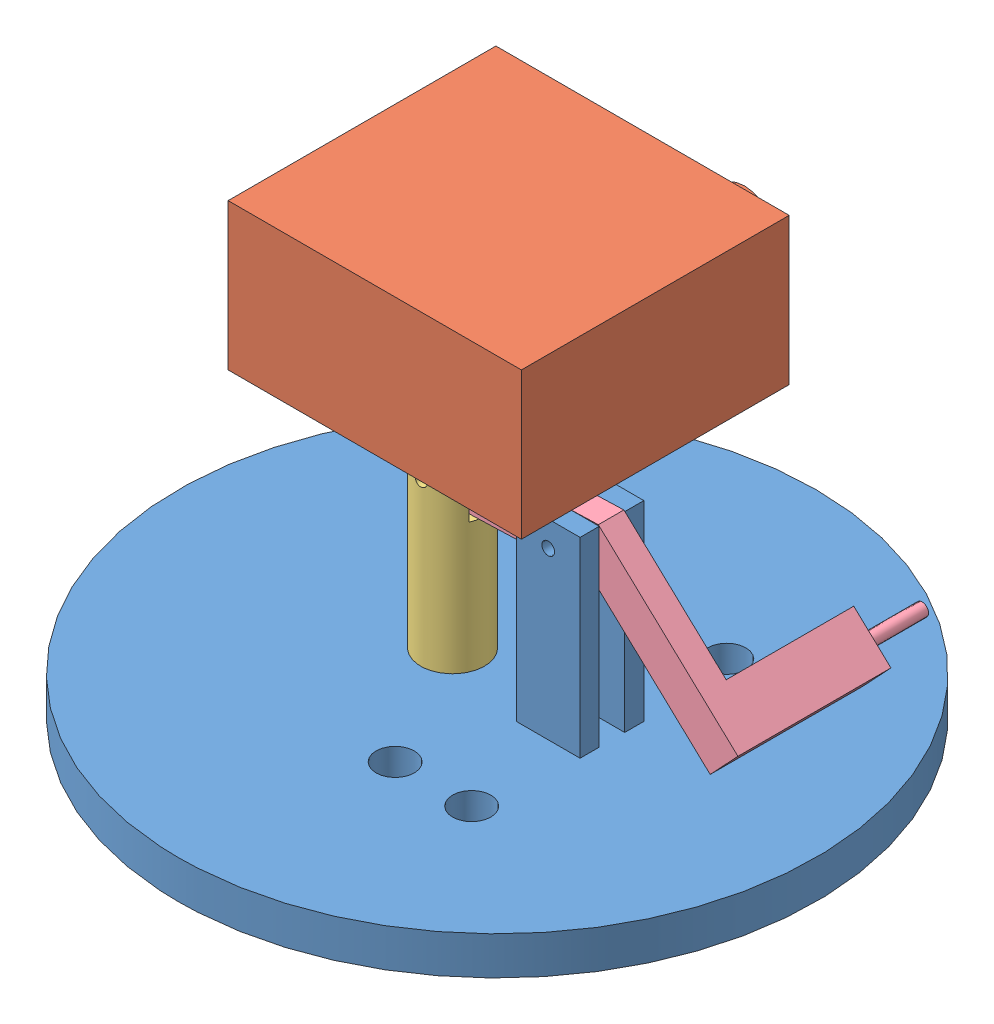
SolidWorks assembly Rückseite, configuration Standard. Lengths in mm.
Overall size (50 36.32 50).
4 component instances, 4 part files, 6 mates.
Components (placement in the parent):
- Backside-1: Backside [Standard] at (-0.7502 -6.4244 50) size (50 18 50)
- servo-1: servo [Standard] at (-8.4227 28.0756 59.9289) x (1 0 0) z (0 1 0) size (23 24.5 11.5)
- Drücker-1: Drücker [Standard] at (-2.5879 -8.2484 21.7522) size (5 20 5)
- Hebel-1: Hebel [Standard] at (9.2498 9.5756 49) x (0.999476 0.032383 0) z (0 0 1) size (25.61 12.86 17)
Mates (geometry in assembly coordinates):
- Konzentrisch1: concentric aligned: cylinder of Drücker-1 through (-0.7502 11.7516 50) axis (0 -1 0) radius 2.5; cylinder of Backside-1 through (-0.7502 -3.4244 50) axis (0 -1 0) radius 2.5
- Konzentrisch2: concentric anti-aligned: cylinder of Backside-1 through (9.2498 9.5756 42.5) axis (0 0 1) radius 0.5; cylinder of Hebel-1 through (9.2498 9.5756 51) axis (0 0 -1) radius 0.5
- Deckungsgleich1: coincident anti-aligned: plane of Backside-1 through (6.7498 11.5756 51) normal (0 0 -1); plane of Hebel-1 through (9.2498 9.5756 51) normal (0 0 1)
- Parallel1: parallel anti-aligned: plane of Drücker-1 through (-3.7502 6.7516 49) normal (0 0 1); plane of Hebel-1 through (9.2498 9.5756 49) normal (0 0 -1)
- Tangential2: tangent anti-aligned: cylinder of Drücker-1 through (-0.7502 9.2516 46) axis (0 0 1) radius 0.5; plane of Hebel-1 through (9.266 9.0759 51) normal (-0.032383 0.999476 0)
- Abstand1: distance = 20 mm anti-aligned: plane of servo-1 through (-8.4227 16.5756 38.9289) normal (0 -1 0); plane of Backside-1 through (-0.7502 -3.4244 50) normal (0 1 0)
